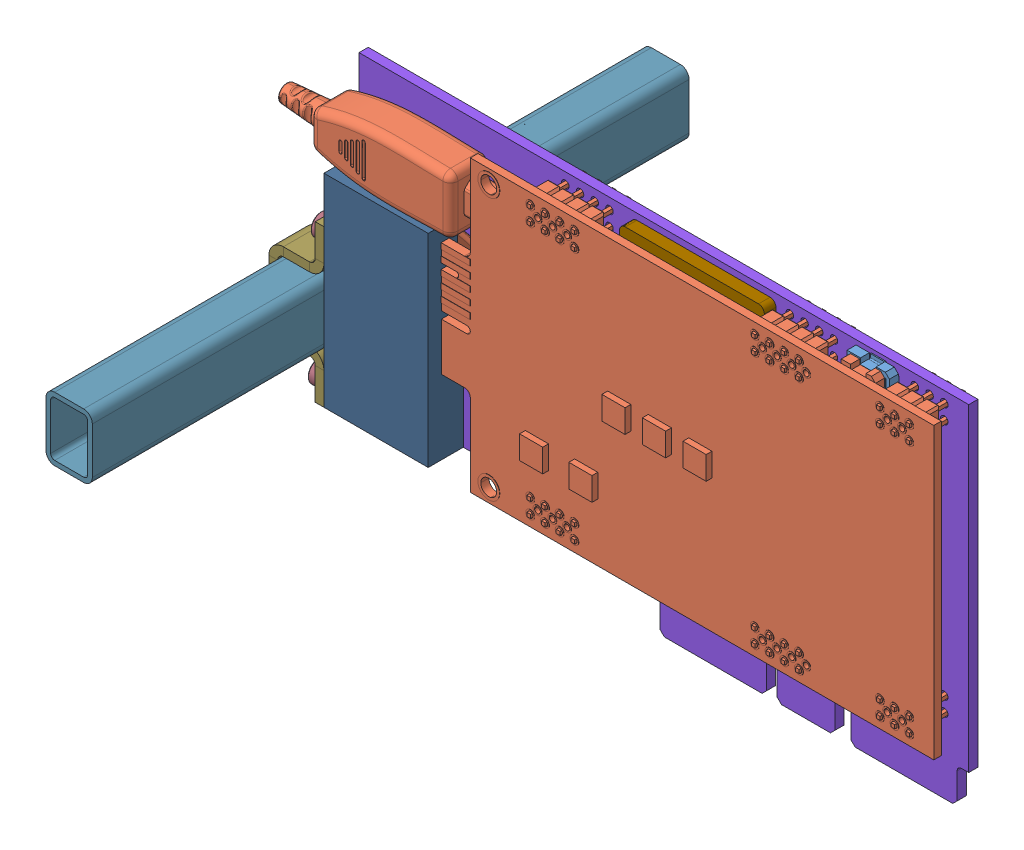
SolidWorks assembly HYDRA_VMM3_CARD_V2, configuration Default. Lengths in mm.
Overall size (114.77 61 103).
32 component instances, 14 part files, 0 mates.
Components (placement in the parent):
- HYDRA_VMM3_CARD_V2(2)-1: HYDRA_VMM3_CARD_V2(2) [Default] at origin size (114.42 61 10.4)
  - FX10A-140S14-SV--3DModel-STEP-1-1: FX10A-140S14-SV--3DModel-STEP-1 [Default] at (124.568 -76.306 2.55) x (-1 0 0) z (0 1 0) size (7.3 3.8 49.1)
    - FX10A-140S14-SV--3DModel-STEP-1-0-1: FX10A-140S14-SV--3DModel-STEP-1-0 [Default] at origin size (7.3 3.8 49.1)
  - VMM3Hybrid_Reworked-1: VMM3Hybrid_Reworked [Default] at (142.318 -82.856 7.65) x (-1 0 0) z (0 0 -1) size (114.42 50 10.4)
    - VMM3Hybrid_Reworked-1-1: VMM3Hybrid_Reworked-1 [Default] at origin size (114.42 50 10.4)
  - R_0603_1608Metric-1: R_0603_1608Metric [Default] at (66.26 -74.8425 -0.05) x (0 1 0) z (0 0 -1) size (1.6 0.8 0.45)
    - R_0603_1608Metric-2-1: R_0603_1608Metric-2 [Default] at origin size (1.6 0.8 0.45)
  - R_0603_1608Metric-2: R_0603_1608Metric [Default] at (66.26 -56.3375 -0.05) x (0 -1 0) z (0 0 -1) size (1.6 0.8 0.45)
    - R_0603_1608Metric-2-1: R_0603_1608Metric-2 [Default] at origin size (1.6 0.8 0.45)
  - LED_0603_1608Metric-1: LED_0603_1608Metric [Default] at (64.67 -56.36 -0.05) x (0 -1 0) z (0 0 -1) size (1.6 0.8 1.1)
    - LED_0603_1608Metric-3-1: LED_0603_1608Metric-3 [Default] at origin size (1.6 0.8 1.1)
  - 20449-001E-03-1: 20449-001E-03 [Default] at (92.3 -36.78 -0.05) x (0 1 0) z (-1 0 0) size (2.01 0.61 2.01)
    - 20449-001E-03-4-1: 20449-001E-03-4 [Default] at origin size (2.01 0.61 2.01)
  - TMP104YFFR--3DModel-STEP-56544-1: TMP104YFFR--3DModel-STEP-56544 [Default] at (95.206 -58.0935 -0.05) x (0 -1 0) z (1 0 0) size (0.76 0.62 0.96)
    - TMP104YFFR-1: TMP104YFFR [Default] at origin size (0.76 0.62 0.96)
  - Fuse_0603_1608Metric-1: Fuse_0603_1608Metric [Default] at (72.85 -65.31 -0.05) x (-0.707107 0.707107 0) z (0 0 -1) size (1.6 0.8 0.45)
    - Fuse_0603_1608Metric-5-1: Fuse_0603_1608Metric-5 [Default] at origin size (1.6 0.8 0.45)
  - Fuse_0603_1608Metric-2: Fuse_0603_1608Metric [Default] at (67.45 -69.02 -0.05) x (-0.707107 0.707107 0) z (0 0 -1) size (1.6 0.8 0.45)
    - Fuse_0603_1608Metric-5-1: Fuse_0603_1608Metric-5 [Default] at origin size (1.6 0.8 0.45)
  - LED_0603_1608Metric-2: LED_0603_1608Metric [Default] at (64.67 -74.82 -0.05) x (0 1 0) z (0 0 -1) size (1.6 0.8 1.1)
    - LED_0603_1608Metric-3-1: LED_0603_1608Metric-3 [Default] at origin size (1.6 0.8 1.1)
  - 20449-001E-03-2: 20449-001E-03 [Default] at (99.3 -36.78 -0.05) x (0 1 0) z (-1 0 0) size (2.01 0.61 2.01)
    - 20449-001E-03-4-1: 20449-001E-03-4 [Default] at origin size (2.01 0.61 2.01)
  - HYDRA_VMM3_CARD_V2_PCB-1: HYDRA_VMM3_CARD_V2_PCB [Default] at origin size (105.25 61 1.6)
- WaterCooling^HYDRA_VMM3_CARD_V2-1: WaterCooling^HYDRA_VMM3_CARD_V2 [Default] at origin size (83.47 48.92 6.05) (virtual)
  - Copy of HeatPipe_v0^WaterCooling_HYDRA_VMM3_CARD_V2-1: Copy of HeatPipe_v0^WaterCooling_HYDRA_VMM3_CARD_V2 [Default] at origin size (41.4 48 2) (virtual)
  - Copy of HeatPipe_v1^WaterCooling_HYDRA_VMM3_CARD_V2-1: Copy of HeatPipe_v1^WaterCooling_HYDRA_VMM3_CARD_V2 [Default] at origin size (18 35 6.05) (virtual)
  - Copy of HeatPipe_v2^WaterCooling_HYDRA_VMM3_CARD_V2-1: Copy of HeatPipe_v2^WaterCooling_HYDRA_VMM3_CARD_V2 [Default] at origin size (74.97 10.08 1) (virtual)
  - Copy of PipeHolder^WaterCooling_HYDRA_VMM3_CARD_V2-1: Copy of PipeHolder^WaterCooling_HYDRA_VMM3_CARD_V2 [Default] at origin size (9.5 27 6.05) (virtual)
  - socket head cap screw_am-1: socket head cap screw_am [B18.3.1M - 2 x 0.4 x 8 Hex SHCS -- 8NHX] at (33.55 -58.53 4.625) size (10 3.8 3.8)
  - socket head cap screw_am-2: socket head cap screw_am [B18.3.1M - 2 x 0.4 x 8 Hex SHCS -- 8NHX] at (33.55 -80.2183 5.125) x (1 0 0) z (0 -0.158553 0.987351) size (10 3.8 3.8)
- RectangularPipe^HYDRA_VMM3_CARD_V2-1: RectangularPipe^HYDRA_VMM3_CARD_V2 [Default] at origin size (8 11 103) (virtual)
